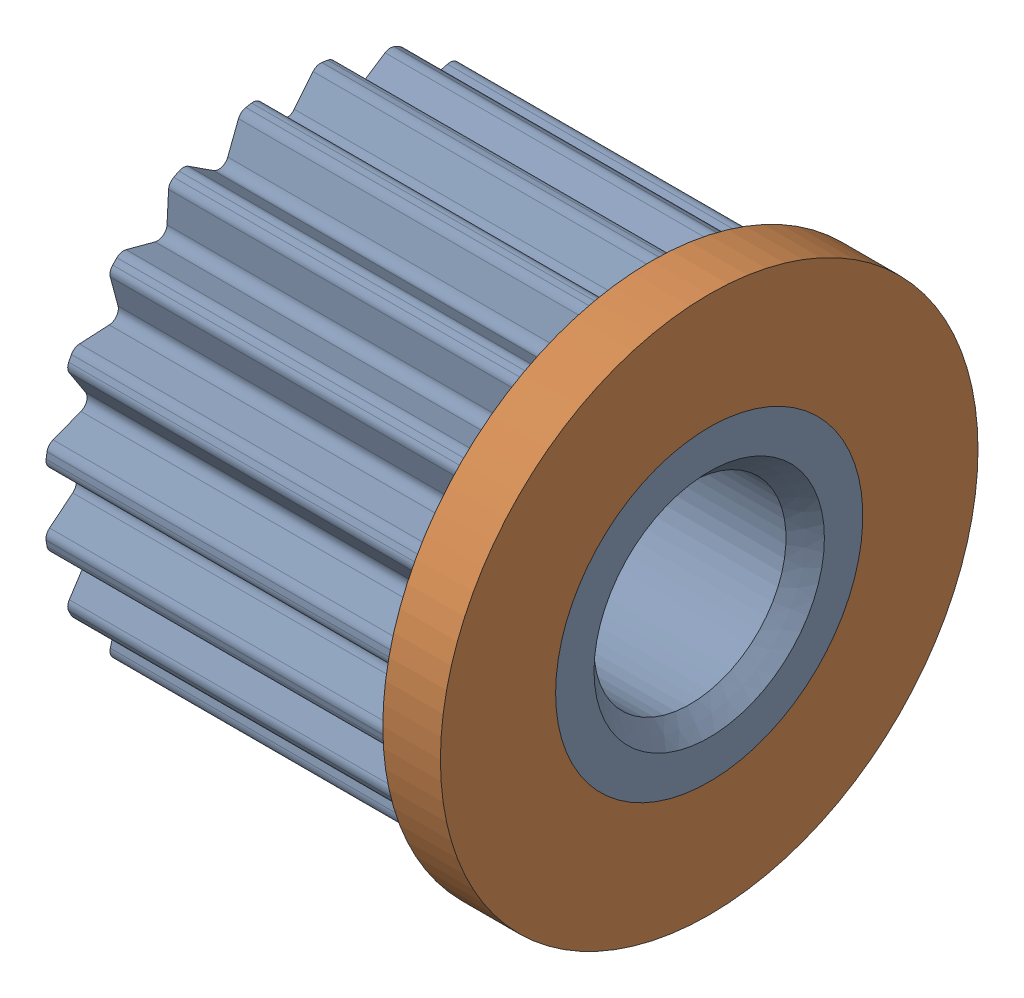
SolidWorks assembly Poulie motrice, configuration Défaut. Lengths in mm.
Overall size (11 14 14).
2 component instances, 2 part files, 1 mates.
Components (placement in the parent):
- Poulie motrice Z=20-1: Poulie motrice Z=20 [Défaut] at origin size (11 12.54 12.54)
- Flasque poulie-1: Flasque poulie [Défaut] at (-16.112 -39.2783 0) size (1.5 14 14)
Mates (geometry in assembly coordinates):
- Coïncidente1: coincident aligned: circle of Poulie motrice Z=20-1; circle of Flasque poulie-1
